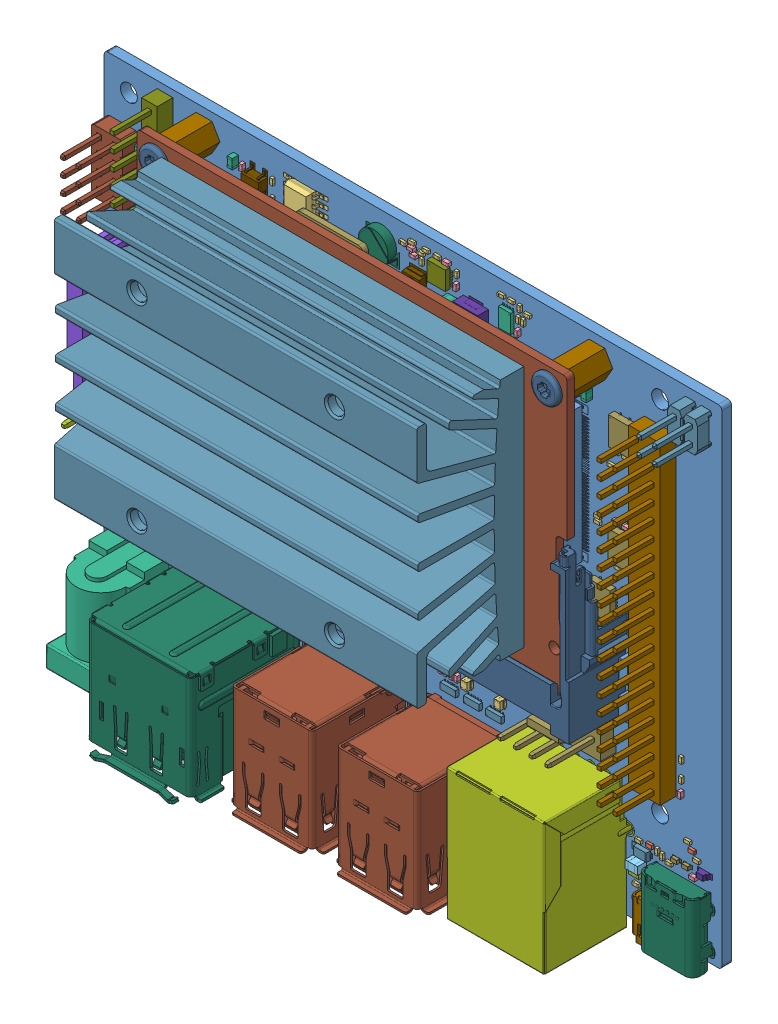
SolidWorks assembly P3450_P3449_A02_P3448_A02, configuration Default. Lengths in mm.
Overall size (100 81.03 30.51).
401 component instances, 71 part files, 0 mates.
Components (placement in the parent):
- 142-13449-1000-A02_ASM-1: 142-13449-1000-A02_ASM [Default] at origin size (100 81.03 23.18)
  - 142-13449-1000-A02-1: 142-13449-1000-A02 [Default] at origin size (100 79 1.57)
  - 315-1109-000_1-1: 315-1109-000_1 [Default] at (5.6 4.9 1.575) x (-1 0 0) z (0 0 1) size (4.5 3.5 0.8)
  - 0402_H040-1: 0402_H040 [Default] at (8 -0.825 1.575) size (1 0.5 0.4)
  - 0402_H060-1: 0402_H060 [Default] at (1 5 1.575) x (0 -1 0) z (0 0 1) size (1 0.5 0.6)
  - 0402_H040-2: 0402_H040 [Default] at (9.9 -0.3 1.575) size (1 0.5 0.4)
  - 0402_H040-3: 0402_H040 [Default] at (8.296 51.194 1.575) x (-1 0 0) z (0 0 1) size (1 0.5 0.4)
  - 0402_H040-4: 0402_H040 [Default] at (76.2 36.9 1.575) x (-1 0 0) z (0 0 1) size (1 0.5 0.4)
  - 0402_H040-5: 0402_H040 [Default] at (37.8 2.87 1.575) x (0 -1 0) z (0 0 1) size (1 0.5 0.4)
  - 0402_H040-6: 0402_H040 [Default] at (38.6 2.87 1.575) x (0 -1 0) z (0 0 1) size (1 0.5 0.4)
  - 0402_H060-2: 0402_H060 [Default] at (14.2 7.7 1.575) x (0 -1 0) z (0 0 1) size (1 0.5 0.6)
  - 0402_H040-7: 0402_H040 [Default] at (64 27.5 1.575) x (-1 0 0) z (0 0 1) size (1 0.5 0.4)
  - 0402_H060-3: 0402_H060 [Default] at (18.6 43.15 1.575) x (-1 0 0) z (0 0 1) size (1 0.5 0.6)
  - 0402_H060-4: 0402_H060 [Default] at (65.5 52.8 1.575) x (0 1 0) z (0 0 1) size (1 0.5 0.6)
  - 0402_H060-5: 0402_H060 [Default] at (64 28.4 1.575) x (-1 0 0) z (0 0 1) size (1 0.5 0.6)
  - 0402_H040-8: 0402_H040 [Default] at (60.95 25.85 1.575) size (1 0.5 0.4)
  - 0402_H060-6: 0402_H060 [Default] at (17.3 7.7 1.575) x (0 -1 0) z (0 0 1) size (1 0.5 0.6)
  - 0402_H060-7: 0402_H060 [Default] at (18.6 7.7 1.575) x (0 -1 0) z (0 0 1) size (1 0.5 0.6)
  - 0402_H060-8: 0402_H060 [Default] at (12.9 7.7 1.575) x (0 -1 0) z (0 0 1) size (1 0.5 0.6)
  - 0402_H060-9: 0402_H060 [Default] at (80.9 37.7 1.575) x (-1 0 0) z (0 0 1) size (1 0.5 0.6)
  - 0402_H040-9: 0402_H040 [Default] at (79.5 31.3 1.575) size (1 0.5 0.4)
  - 0402_H040-10: 0402_H040 [Default] at (81 31.3 1.575) x (-1 0 0) z (0 0 1) size (1 0.5 0.4)
  - 0402_H060-10: 0402_H060 [Default] at (79.3 37.7 1.575) size (1 0.5 0.6)
  - 0402_H060-11: 0402_H060 [Default] at (74.8 4.05 1.575) x (-1 0 0) z (0 0 1) size (1 0.5 0.6)
  - 0402_H040-11: 0402_H040 [Default] at (65.675 6.15 1.575) x (0 -1 0) z (0 0 1) size (1 0.5 0.4)
  - 0402_H060-12: 0402_H060 [Default] at (67.7 6.85 1.575) x (0 1 0) z (0 0 1) size (1 0.5 0.6)
  - 0402_H040-12: 0402_H040 [Default] at (64.475 5.8 1.575) x (-1 0 0) z (0 0 1) size (1 0.5 0.4)
  - 0402_H040-13: 0402_H040 [Default] at (67.725 5.325 1.575) x (0 1 0) z (0 0 1) size (1 0.5 0.4)
  - 0402_H060-13: 0402_H060 [Default] at (46.1 59.45 1.575) size (1 0.5 0.6)
  - 0402_H040-14: 0402_H040 [Default] at (44.65 59.45 1.575) size (1 0.5 0.4)
  - 0402_H040-15: 0402_H040 [Default] at (46.1 60.25 1.575) size (1 0.5 0.4)
  - 0402_H060-14: 0402_H060 [Default] at (53.35 57.7 1.575) x (0 -1 0) z (0 0 1) size (1 0.5 0.6)
  - 0402_H040-16: 0402_H040 [Default] at (47.6 59.45 1.575) size (1 0.5 0.4)
  - 0402_H040-17: 0402_H040 [Default] at (48.4 60.25 1.575) size (1 0.5 0.4)
  - 0402_H040-18: 0402_H040 [Default] at (47.7 58.325 1.575) x (0 1 0) z (0 0 1) size (1 0.5 0.4)
  - 0402_H060-15: 0402_H060 [Default] at (46.5 58.65 1.575) x (-1 0 0) z (0 0 1) size (1 0.5 0.6)
  - 0402_H060-16: 0402_H060 [Default] at (51.8 60.25 1.575) size (1 0.5 0.6)
  - 0402_H040-19: 0402_H040 [Default] at (53.35 59.4 1.575) x (0 -1 0) z (0 0 1) size (1 0.5 0.4)
  - 0402_H040-20: 0402_H040 [Default] at (50.2 60.25 1.575) x (-1 0 0) z (0 0 1) size (1 0.5 0.4)
  - 0402_H060-17: 0402_H060 [Default] at (18.6 43.95 1.575) x (-1 0 0) z (0 0 1) size (1 0.5 0.6)
  - 0402_H060-18: 0402_H060 [Default] at (52.75 2.9 1.575) x (0 -1 0) z (0 0 1) size (1 0.5 0.6)
  - 0402_H060-19: 0402_H060 [Default] at (22.35 47.4 1.575) x (-1 0 0) z (0 0 1) size (1 0.5 0.6)
  - 0402_H060-20: 0402_H060 [Default] at (20.55 47.4 1.575) x (-1 0 0) z (0 0 1) size (1 0.5 0.6)
  - 0402_H060-21: 0402_H060 [Default] at (21.95 34.55 1.575) x (0 -1 0) z (0 0 1) size (1 0.5 0.6)
  - 0402_H060-22: 0402_H060 [Default] at (21.05 34.55 1.575) x (0 -1 0) z (0 0 1) size (1 0.5 0.6)
  - 0402_H060-23: 0402_H060 [Default] at (53.55 2.9 1.575) x (0 -1 0) z (0 0 1) size (1 0.5 0.6)
  - 0402_H060-24: 0402_H060 [Default] at (25.4 54 1.575) x (-1 0 0) z (0 0 1) size (1 0.5 0.6)
  - 0402_H060-25: 0402_H060 [Default] at (24 34.58 1.575) x (0 -1 0) z (0 0 1) size (1 0.5 0.6)
  - 0402_H040-21: 0402_H040 [Default] at (55.6 2.95 1.575) x (0 -1 0) z (0 0 1) size (1 0.5 0.4)
  - 0402_H040-22: 0402_H040 [Default] at (20.13 34.53 1.575) x (0 1 0) z (0 0 1) size (1 0.5 0.4)
  - 0402_H060-26: 0402_H060 [Default] at (18.4 35.15 1.575) x (0 1 0) z (0 0 1) size (1 0.5 0.6)
  - 0402_H060-27: 0402_H060 [Default] at (18.4 36.75 1.575) x (0 1 0) z (0 0 1) size (1 0.5 0.6)
  - 0402_H040-23: 0402_H040 [Default] at (39.6 2.87 1.575) x (0 -1 0) z (0 0 1) size (1 0.5 0.4)
  - 0402_H040-24: 0402_H040 [Default] at (40.4 2.87 1.575) x (0 -1 0) z (0 0 1) size (1 0.5 0.4)
  - 0402_H040-25: 0402_H040 [Default] at (60.95 2.95 1.575) x (0 -1 0) z (0 0 1) size (1 0.5 0.4)
  - 0402_H040-26: 0402_H040 [Default] at (60.15 2.95 1.575) x (0 -1 0) z (0 0 1) size (1 0.5 0.4)
  - 0402_H040-27: 0402_H040 [Default] at (54.8 2.95 1.575) x (0 -1 0) z (0 0 1) size (1 0.5 0.4)
  - 0402_H040-28: 0402_H040 [Default] at (31.6 54 1.575) size (1 0.5 0.4)
  - 0402_H040-29: 0402_H040 [Default] at (27.4 54 1.575) size (1 0.5 0.4)
  - 0402_H040-30: 0402_H040 [Default] at (29.6 54 1.575) x (-1 0 0) z (0 0 1) size (1 0.5 0.4)
  - 0402_H040-31: 0402_H040 [Default] at (63.775 -14.475 1.575) size (1 0.5 0.4)
  - 0402_H040-32: 0402_H040 [Default] at (63.775 -15.275 1.575) size (1 0.5 0.4)
  - 0402_H040-33: 0402_H040 [Default] at (8.025 41.475 1.575) x (-1 0 0) z (0 0 1) size (1 0.5 0.4)
  - 0402_H060-28: 0402_H060 [Default] at (63.95 1.25 1.575) x (0 1 0) z (0 0 1) size (1 0.5 0.6)
  - 0402_H060-29: 0402_H060 [Default] at (2.95 54.05 1.575) x (0 1 0) z (0 0 1) size (1 0.5 0.6)
  - 0402_H040-34: 0402_H040 [Default] at (92.2 -3.45 1.575) x (-1 0 0) z (0 0 1) size (1 0.5 0.4)
  - 0402_H060-30: 0402_H060 [Default] at (32.85 7.7 1.575) x (0 -1 0) z (0 0 1) size (1 0.5 0.6)
  - 0402_H060-31: 0402_H060 [Default] at (27.25 7.7 1.575) x (0 -1 0) z (0 0 1) size (1 0.5 0.6)
  - 0402_H060-32: 0402_H060 [Default] at (31.25 7.7 1.575) x (0 -1 0) z (0 0 1) size (1 0.5 0.6)
  - 0402_H060-33: 0402_H060 [Default] at (28.85 7.7 1.575) x (0 -1 0) z (0 0 1) size (1 0.5 0.6)
  - 0402_H060-34: 0402_H060 [Default] at (32.05 7.7 1.575) x (0 -1 0) z (0 0 1) size (1 0.5 0.6)
  - 0402_H060-35: 0402_H060 [Default] at (28.05 7.7 1.575) x (0 -1 0) z (0 0 1) size (1 0.5 0.6)
  - 0402_H060-36: 0402_H060 [Default] at (30.45 7.7 1.575) x (0 -1 0) z (0 0 1) size (1 0.5 0.6)
  - 0402_H060-37: 0402_H060 [Default] at (29.65 7.7 1.575) x (0 -1 0) z (0 0 1) size (1 0.5 0.6)
  - 0402_H060-38: 0402_H060 [Default] at (24.65 6.41 1.575) x (0 -1 0) z (0 0 1) size (1 0.5 0.6)
  - 0402_H060-39: 0402_H060 [Default] at (25.85 6.41 1.575) x (0 -1 0) z (0 0 1) size (1 0.5 0.6)
  - 0402_H060-40: 0402_H060 [Default] at (4.2 36.5 1.575) x (0 1 0) z (0 0 1) size (1 0.5 0.6)
  - 0402_H060-41: 0402_H060 [Default] at (89.7 4.7 1.575) x (0 -1 0) z (0 0 1) size (1 0.5 0.6)
  - 0402_H060-42: 0402_H060 [Default] at (82.5 3.8 1.575) x (0 -1 0) z (0 0 1) size (1 0.5 0.6)
  - 0402_H060-43: 0402_H060 [Default] at (12.65 49.7 1.575) size (1 0.5 0.6)
  - 0402_H060-44: 0402_H060 [Default] at (11.2 50.15 1.575) x (0 -1 0) z (0 0 1) size (1 0.5 0.6)
  - 0402_H060-45: 0402_H060 [Default] at (26.5 34.55 1.575) x (0 -1 0) z (0 0 1) size (1 0.5 0.6)
  - 0402_H060-46: 0402_H060 [Default] at (29.9 34.5 1.575) x (0 -1 0) z (0 0 1) size (1 0.5 0.6)
  - 0402_H060-47: 0402_H060 [Default] at (31.7 40.15 1.575) x (0 1 0) z (0 0 1) size (1 0.5 0.6)
  - 0402_H060-48: 0402_H060 [Default] at (31.15 42.5 1.575) x (0 1 0) z (0 0 1) size (1 0.5 0.6)
  - 0402_H060-49: 0402_H060 [Default] at (19.2 47.05 1.575) x (0 1 0) z (0 0 1) size (1 0.5 0.6)
  - 0402_H060-50: 0402_H060 [Default] at (17.95 42 1.575) x (0 -1 0) z (0 0 1) size (1 0.5 0.6)
  - 0402_H060-51: 0402_H060 [Default] at (27.3 48.25 1.575) x (0 1 0) z (0 0 1) size (1 0.5 0.6)
  - 0402_H060-52: 0402_H060 [Default] at (31.7 37.85 1.575) x (0 -1 0) z (0 0 1) size (1 0.5 0.6)
  - 0402_H060-53: 0402_H060 [Default] at (29.6 48.35 1.575) x (0 1 0) z (0 0 1) size (1 0.5 0.6)
  - 0402_H060-54: 0402_H060 [Default] at (18.8 38.75 1.575) x (-1 0 0) z (0 0 1) size (1 0.5 0.6)
  - 0402_H060-55: 0402_H060 [Default] at (18.7 57.2 1.575) x (0 -1 0) z (0 0 1) size (1 0.5 0.6)
  - 0402_H060-56: 0402_H060 [Default] at (34.1 2.9 1.575) x (0 -1 0) z (0 0 1) size (1 0.5 0.6)
  - 0402_H060-57: 0402_H060 [Default] at (35.8 2.9 1.575) x (0 -1 0) z (0 0 1) size (1 0.5 0.6)
  - 0402_H060-58: 0402_H060 [Default] at (34.9 2.9 1.575) x (0 -1 0) z (0 0 1) size (1 0.5 0.6)
  - 0402_H060-59: 0402_H060 [Default] at (36.6 2.9 1.575) x (0 -1 0) z (0 0 1) size (1 0.5 0.6)
  - 0402_H060-60: 0402_H060 [Default] at (11.325 44.725 1.575) size (1 0.5 0.6)
  - 0402_H060-61: 0402_H060 [Default] at (50.95 2.9 1.575) x (0 -1 0) z (0 0 1) size (1 0.5 0.6)
  - 0402_H060-62: 0402_H060 [Default] at (51.75 2.9 1.575) x (0 -1 0) z (0 0 1) size (1 0.5 0.6)
  - 0402_H060-63: 0402_H060 [Default] at (11.55 39.7 1.575) size (1 0.5 0.6)
  - 0402_H060-64: 0402_H060 [Default] at (9.5 -8.5 1.575) x (-1 0 0) z (0 0 1) size (1 0.5 0.6)
  - 0402_H060-65: 0402_H060 [Default] at (61.35 38.05 1.575) x (0 -1 0) z (0 0 1) size (1 0.5 0.6)
  - 0402_H060-66: 0402_H060 [Default] at (60.55 38.05 1.575) x (0 -1 0) z (0 0 1) size (1 0.5 0.6)
  - 0402_H060-67: 0402_H060 [Default] at (29.3 25.65 1.575) x (0 -1 0) z (0 0 1) size (1 0.5 0.6)
  - 0402_H060-68: 0402_H060 [Default] at (63.3 56.2 1.575) x (0 1 0) z (0 0 1) size (1 0.5 0.6)
  - 0402_H060-69: 0402_H060 [Default] at (20.5 54.2 1.575) size (1 0.5 0.6)
  - 0402_H060-70: 0402_H060 [Default] at (60.1 32.15 1.575) x (0 1 0) z (0 0 1) size (1 0.5 0.6)
  - 0402_H060-71: 0402_H060 [Default] at (60.9 32.15 1.575) x (0 1 0) z (0 0 1) size (1 0.5 0.6)
  - 0402_H060-72: 0402_H060 [Default] at (18.6 44.85 1.575) size (1 0.5 0.6)
  - 0402_H060-73: 0402_H060 [Default] at (18.6 45.65 1.575) size (1 0.5 0.6)
  - 0402_H060-74: 0402_H060 [Default] at (18.1 27.25 1.575) size (1 0.5 0.6)
  - 0402_H060-75: 0402_H060 [Default] at (15.1 7.7 1.575) x (0 -1 0) z (0 0 1) size (1 0.5 0.6)
  - 0402_H060-76: 0402_H060 [Default] at (16.4 7.7 1.575) x (0 -1 0) z (0 0 1) size (1 0.5 0.6)
  - 0402_H060-77: 0402_H060 [Default] at (20.8 7.7 1.575) x (0 -1 0) z (0 0 1) size (1 0.5 0.6)
  - 0402_H060-78: 0402_H060 [Default] at (19.5 7.7 1.575) x (0 -1 0) z (0 0 1) size (1 0.5 0.6)
  - 0402_H060-79: 0402_H060 [Default] at (21.9 2.8 1.575) size (1 0.5 0.6)
  - 0402_H060-80: 0402_H060 [Default] at (12.75 29 1.575) size (1 0.5 0.6)
  - 0402_H060-81: 0402_H060 [Default] at (10.225 5.1 1.575) size (1 0.5 0.6)
  - 0402_H060-82: 0402_H060 [Default] at (22.8 27.65 1.575) x (0 1 0) z (0 0 1) size (1 0.5 0.6)
  - 0402_H060-83: 0402_H060 [Default] at (18.85 25.15 1.575) x (0 -1 0) z (0 0 1) size (1 0.5 0.6)
  - 0402_H060-84: 0402_H060 [Default] at (17.95 40.1 1.575) x (0 1 0) z (0 0 1) size (1 0.5 0.6)
  - 0402_H040-35: 0402_H040 [Default] at (20.8 6.2 1.575) x (0 1 0) z (0 0 1) size (1 0.5 0.4)
  - 0402_H040-36: 0402_H040 [Default] at (76 22.7 1.575) size (1 0.5 0.4)
  - 0402_H040-37: 0402_H040 [Default] at (23.7 26.85 1.575) x (0 1 0) z (0 0 1) size (1 0.5 0.4)
  - 0402_H040-38: 0402_H040 [Default] at (18 25.15 1.575) x (0 1 0) z (0 0 1) size (1 0.5 0.4)
  - 0402_H040-39: 0402_H040 [Default] at (17.3 28.25 1.575) x (-1 0 0) z (0 0 1) size (1 0.5 0.4)
  - 0402_H040-40: 0402_H040 [Default] at (13.15 4.2 1.575) x (0 -1 0) z (0 0 1) size (1 0.5 0.4)
  - 0402_H040-41: 0402_H040 [Default] at (17.2 30.15 1.575) x (0 -1 0) z (0 0 1) size (1 0.5 0.4)
  - 0402_H040-42: 0402_H040 [Default] at (14.2 6.2 1.575) x (0 1 0) z (0 0 1) size (1 0.5 0.4)
  - 0402_H040-43: 0402_H040 [Default] at (12.9 6.2 1.575) x (0 1 0) z (0 0 1) size (1 0.5 0.4)
  - 0402_H040-44: 0402_H040 [Default] at (15.1 6.2 1.575) x (0 1 0) z (0 0 1) size (1 0.5 0.4)
  - 0402_H040-45: 0402_H040 [Default] at (16.4 6.2 1.575) x (0 1 0) z (0 0 1) size (1 0.5 0.4)
  - 0402_H040-46: 0402_H040 [Default] at (19.5 6.2 1.575) x (0 1 0) z (0 0 1) size (1 0.5 0.4)
  - 0402_H040-47: 0402_H040 [Default] at (17.3 6.2 1.575) x (0 1 0) z (0 0 1) size (1 0.5 0.4)
  - 0402_H040-48: 0402_H040 [Default] at (18.6 6.2 1.575) x (0 1 0) z (0 0 1) size (1 0.5 0.4)
  - 0402_H040-49: 0402_H040 [Default] at (24.2 24.55 1.575) x (0 1 0) z (0 0 1) size (1 0.5 0.4)
  - 0402_H040-50: 0402_H040 [Default] at (23.5 54.9 1.575) x (0 1 0) z (0 0 1) size (1 0.5 0.4)
  - 0402_H040-51: 0402_H040 [Default] at (13.2 39.75 1.575) x (-1 0 0) z (0 0 1) size (1 0.5 0.4)
  - 0402_H040-52: 0402_H040 [Default] at (80.7 47.4 1.575) x (-1 0 0) z (0 0 1) size (1 0.5 0.4)
  - 0402_H040-53: 0402_H040 [Default] at (77.5 22.7 1.575) x (-1 0 0) z (0 0 1) size (1 0.5 0.4)
  - 0402_H040-54: 0402_H040 [Default] at (9.25 -12.75 1.575) x (-1 0 0) z (0 0 1) size (1 0.5 0.4)
  - 0402_H040-55: 0402_H040 [Default] at (9.25 -11.95 1.575) x (-1 0 0) z (0 0 1) size (1 0.5 0.4)
  - 0402_H040-56: 0402_H040 [Default] at (64.475 6.7 1.575) size (1 0.5 0.4)
  - 0402_H040-57: 0402_H040 [Default] at (29.3 24 1.575) x (0 1 0) z (0 0 1) size (1 0.5 0.4)
  - 0402_H040-58: 0402_H040 [Default] at (64.2 32.5 1.575) x (0 1 0) z (0 0 1) size (1 0.5 0.4)
  - 0402_H040-59: 0402_H040 [Default] at (64.15 47.45 1.575) x (0 -1 0) z (0 0 1) size (1 0.5 0.4)
  - 0402_H040-60: 0402_H040 [Default] at (64.2 31 1.575) x (0 -1 0) z (0 0 1) size (1 0.5 0.4)
  - 0402_H040-61: 0402_H040 [Default] at (76.2 36.1 1.575) x (-1 0 0) z (0 0 1) size (1 0.5 0.4)
  - 0402_H040-62: 0402_H040 [Default] at (78.4 45.15 1.575) size (1 0.5 0.4)
  - 0402_H040-63: 0402_H040 [Default] at (81.7 38.6 1.575) size (1 0.5 0.4)
  - 0402_H040-64: 0402_H040 [Default] at (81.7 39.4 1.575) size (1 0.5 0.4)
  - 0402_H040-65: 0402_H040 [Default] at (59.35 51.825 1.575) size (1 0.5 0.4)
  - 0402_H040-66: 0402_H040 [Default] at (60.825 51.825 1.575) x (-1 0 0) z (0 0 1) size (1 0.5 0.4)
  - 0402_H040-67: 0402_H040 [Default] at (89.7 9.5 1.575) x (0 1 0) z (0 0 1) size (1 0.5 0.4)
  - 0402_H040-68: 0402_H040 [Default] at (89.7 6.7 1.575) x (0 1 0) z (0 0 1) size (1 0.5 0.4)
  - 0402_H040-69: 0402_H040 [Default] at (3.9 34.2 1.575) x (0 -1 0) z (0 0 1) size (1 0.5 0.4)
  - 0402_H040-70: 0402_H040 [Default] at (5.1 35 1.575) x (0 1 0) z (0 0 1) size (1 0.5 0.4)
  - 0402_H040-71: 0402_H040 [Default] at (32.85 5.81 1.575) x (0 -1 0) z (0 0 1) size (1 0.5 0.4)
  - 0402_H040-72: 0402_H040 [Default] at (32.05 5.81 1.575) x (0 -1 0) z (0 0 1) size (1 0.5 0.4)
  - 0402_H040-73: 0402_H040 [Default] at (27.25 5.81 1.575) x (0 -1 0) z (0 0 1) size (1 0.5 0.4)
  - 0402_H040-74: 0402_H040 [Default] at (28.05 5.81 1.575) x (0 -1 0) z (0 0 1) size (1 0.5 0.4)
  - 0402_H040-75: 0402_H040 [Default] at (31.25 5.81 1.575) x (0 -1 0) z (0 0 1) size (1 0.5 0.4)
  - 0402_H040-76: 0402_H040 [Default] at (30.45 5.81 1.575) x (0 -1 0) z (0 0 1) size (1 0.5 0.4)
  - 0402_H040-77: 0402_H040 [Default] at (28.85 5.81 1.575) x (0 -1 0) z (0 0 1) size (1 0.5 0.4)
  - 0402_H040-78: 0402_H040 [Default] at (29.65 5.81 1.575) x (0 -1 0) z (0 0 1) size (1 0.5 0.4)
  - 0402_H040-79: 0402_H040 [Default] at (13.5 52.9 1.575) x (-1 0 0) z (0 0 1) size (1 0.5 0.4)
  - 0402_H040-80: 0402_H040 [Default] at (22.35 4 1.575) x (0 -1 0) z (0 0 1) size (1 0.5 0.4)
  - 0402_H040-81: 0402_H040 [Default] at (21.55 4 1.575) x (0 1 0) z (0 0 1) size (1 0.5 0.4)
  - 0402_H040-82: 0402_H040 [Default] at (25.85 4.9 1.575) x (0 -1 0) z (0 0 1) size (1 0.5 0.4)
  - 0402_H040-83: 0402_H040 [Default] at (11.8 52.9 1.575) size (1 0.5 0.4)
  - 0402_H040-84: 0402_H040 [Default] at (9.432 51.594 1.575) x (0 -1 0) z (0 0 1) size (1 0.5 0.4)
  - 0402_H040-85: 0402_H040 [Default] at (8.975 50.3 1.575) size (1 0.5 0.4)
  - 0402_H040-86: 0402_H040 [Default] at (82.8 -5.3 1.575) x (-1 0 0) z (0 0 1) size (1 0.5 0.4)
  - 0402_H040-87: 0402_H040 [Default] at (82.4 -11.6 1.575) x (-1 0 0) z (0 0 1) size (1 0.5 0.4)
  - 0402_H040-88: 0402_H040 [Default] at (22.8 26.05 1.575) x (0 1 0) z (0 0 1) size (1 0.5 0.4)
  - 0402_H040-89: 0402_H040 [Default] at (20.8 28.25 1.575) size (1 0.5 0.4)
  - 0402_H040-90: 0402_H040 [Default] at (20.8 24.65 1.575) x (-1 0 0) z (0 0 1) size (1 0.5 0.4)
  - 0402_H040-91: 0402_H040 [Default] at (18.1 26.45 1.575) size (1 0.5 0.4)
  - 0402_H040-92: 0402_H040 [Default] at (24.65 8.41 1.575) x (0 1 0) z (0 0 1) size (1 0.5 0.4)
  - 0402_H040-93: 0402_H040 [Default] at (25.85 8.41 1.575) x (0 1 0) z (0 0 1) size (1 0.5 0.4)
  - 0402_H040-94: 0402_H040 [Default] at (3.8 54.4 1.575) x (0 -1 0) z (0 0 1) size (1 0.5 0.4)
  - 0402_H040-95: 0402_H040 [Default] at (2.45 44.45 1.575) x (0 -1 0) z (0 0 1) size (1 0.5 0.4)
  - 0402_H040-96: 0402_H040 [Default] at (24.65 4.9 1.575) x (0 1 0) z (0 0 1) size (1 0.5 0.4)
  - 0402_H040-97: 0402_H040 [Default] at (22.15 7.6 1.575) x (-1 0 0) z (0 0 1) size (1 0.5 0.4)
  - 0402_H040-98: 0402_H040 [Default] at (79.2 47.4 1.575) size (1 0.5 0.4)
  - 0402_H040-99: 0402_H040 [Default] at (19 28.25 1.575) size (1 0.5 0.4)
  - 0402_H040-100: 0402_H040 [Default] at (9.65 9.7 1.575) x (0 -1 0) z (0 0 1) size (1 0.5 0.4)
  - 0402_H040-101: 0402_H040 [Default] at (28.35 34.45 1.575) x (0 1 0) z (0 0 1) size (1 0.5 0.4)
  - 0402_H040-102: 0402_H040 [Default] at (25.2 34.55 1.575) x (0 1 0) z (0 0 1) size (1 0.5 0.4)
  - 0402_H040-103: 0402_H040 [Default] at (10.625 6.35 1.575) x (0 -1 0) z (0 0 1) size (1 0.5 0.4)
  - 0402_H040-104: 0402_H040 [Default] at (9.825 6.35 1.575) x (0 1 0) z (0 0 1) size (1 0.5 0.4)
  - 0402_H040-105: 0402_H040 [Default] at (4.775 42.975 1.575) x (0 1 0) z (0 0 1) size (1 0.5 0.4)
  - 0402_H040-106: 0402_H040 [Default] at (19.8 32.9 1.575) x (-1 0 0) z (0 0 1) size (1 0.5 0.4)
  - 0402_H040-107: 0402_H040 [Default] at (22.35 24.65 1.575) x (-1 0 0) z (0 0 1) size (1 0.5 0.4)
  - 0402_H040-108: 0402_H040 [Default] at (62.4 54.7 1.575) size (1 0.5 0.4)
  - 0402_H040-109: 0402_H040 [Default] at (62.2 60.05 1.575) x (-1 0 0) z (0 0 1) size (1 0.5 0.4)
  - 0402_H040-110: 0402_H040 [Default] at (23.5 57.5 1.575) x (0 1 0) z (0 0 1) size (1 0.5 0.4)
  - 0402_H040-111: 0402_H040 [Default] at (12.8 44.725 1.575) size (1 0.5 0.4)
  - 0402_H040-112: 0402_H040 [Default] at (21.8 31.45 1.575) x (0 1 0) z (0 0 1) size (1 0.5 0.4)
  - 0402_H040-113: 0402_H040 [Default] at (19.25 34.55 1.575) x (0 1 0) z (0 0 1) size (1 0.5 0.4)
  - 0402_H040-114: 0402_H040 [Default] at (0.95 41.55 1.575) size (1 0.5 0.4)
  - 0402_H040-115: 0402_H040 [Default] at (64.1 58 1.575) x (0 1 0) z (0 0 1) size (1 0.5 0.4)
  - 0402_H040-116: 0402_H040 [Default] at (63.3 58 1.575) x (0 -1 0) z (0 0 1) size (1 0.5 0.4)
  - 0402_H040-117: 0402_H040 [Default] at (63.55 59.7 1.575) x (0 -1 0) z (0 0 1) size (1 0.5 0.4)
  - 0402_H060-85: 0402_H060 [Default] at (71.175 4 1.575) x (-1 0 0) z (0 0 1) size (1 0.5 0.6)
  - 0402_H040-118: 0402_H040 [Default] at (86.6 -5.6 1.575) x (0 1 0) z (0 0 1) size (1 0.5 0.4)
  - 0402_H040-119: 0402_H040 [Default] at (85.8 -5.3 1.575) x (0 1 0) z (0 0 1) size (1 0.5 0.4)
  - 0402_H040-120: 0402_H040 [Default] at (10.25 51.6 1.575) x (0 1 0) z (0 0 1) size (1 0.5 0.4)
  - 0402_H040-121: 0402_H040 [Default] at (80.5 28.55 1.575) size (1 0.5 0.4)
  - 0402_H040-122: 0402_H040 [Default] at (13.95 4.2 1.575) x (0 -1 0) z (0 0 1) size (1 0.5 0.4)
  - 0402_H040-123: 0402_H040 [Default] at (15.35 4.2 1.575) x (0 -1 0) z (0 0 1) size (1 0.5 0.4)
  - 0402_H040-124: 0402_H040 [Default] at (16.15 4.2 1.575) x (0 -1 0) z (0 0 1) size (1 0.5 0.4)
  - 0402_H040-125: 0402_H040 [Default] at (20.55 4.2 1.575) x (0 -1 0) z (0 0 1) size (1 0.5 0.4)
  - 0402_H040-126: 0402_H040 [Default] at (19.75 4.2 1.575) x (0 -1 0) z (0 0 1) size (1 0.5 0.4)
  - 0402_H040-127: 0402_H040 [Default] at (17.6 4.2 1.575) x (0 -1 0) z (0 0 1) size (1 0.5 0.4)
  - 0402_H040-128: 0402_H040 [Default] at (18.4 4.2 1.575) x (0 -1 0) z (0 0 1) size (1 0.5 0.4)
  - 0402_H060-86: 0402_H060 [Default] at (64.25 -13.325 1.575) x (0 -1 0) z (0 0 1) size (1 0.5 0.6)
  - 0402_H060-87: 0402_H060 [Default] at (64.225 -11.825 1.575) x (0 1 0) z (0 0 1) size (1 0.5 0.6)
  - 0402_H040-129: 0402_H040 [Default] at (63.8 -6.85 1.575) x (0 1 0) z (0 0 1) size (1 0.5 0.4)
  - 0402_H040-130: 0402_H040 [Default] at (81.7 41.95 1.575) size (1 0.5 0.4)
  - 0402_H040-131: 0402_H040 [Default] at (87.75 -6 1.575) x (-1 0 0) z (0 0 1) size (1 0.5 0.4)
  - 0402_H040-132: 0402_H040 [Default] at (82.4 -13.6 1.575) x (-1 0 0) z (0 0 1) size (1 0.5 0.4)
  - 0402_H060-88: 0402_H060 [Default] at (91.75 -5.95 1.575) size (1 0.5 0.6)
  - 0402_H040-133: 0402_H040 [Default] at (3.65 49.25 1.575) x (0 -1 0) z (0 0 1) size (1 0.5 0.4)
  - 0402_H040-134: 0402_H040 [Default] at (2.45 49.25 1.575) x (0 1 0) z (0 0 1) size (1 0.5 0.4)
  - 0402_H040-135: 0402_H040 [Default] at (90.75 -1.45 1.575) x (-1 0 0) z (0 0 1) size (1 0.5 0.4)
  - 0402_H040-136: 0402_H040 [Default] at (8.45 39.55 1.575) x (0 -1 0) z (0 0 1) size (1 0.5 0.4)
  - 0402_H060-89: 0402_H060 [Default] at (8.85 -5.25 1.575) x (-1 0 0) z (0 0 1) size (1 0.5 0.6)
  - 0402_H040-137: 0402_H040 [Default] at (18.6 32.55 1.575) x (0 1 0) z (0 0 1) size (1 0.5 0.4)
  - 0402_H060-90: 0402_H060 [Default] at (4.5 44.45 1.575) x (0 1 0) z (0 0 1) size (1 0.5 0.6)
  - 0402_H040-138: 0402_H040 [Default] at (8.35 2.75 1.575) size (1 0.5 0.4)
  - 0402_H040-139: 0402_H040 [Default] at (9.4 1.95 1.575) size (1 0.5 0.4)
  - 0402_H040-140: 0402_H040 [Default] at (8.2 1.55 1.575) x (0 1 0) z (0 0 1) size (1 0.5 0.4)
  - 0402_H060-91: 0402_H060 [Default] at (8.5 3.875 1.575) x (0 -1 0) z (0 0 1) size (1 0.5 0.6)
  - 0402_H060-92: 0402_H060 [Default] at (-0.8 41.5 1.575) x (-1 0 0) z (0 0 1) size (1 0.5 0.6)
  - 0402_H040-141: 0402_H040 [Default] at (-1.35 7.75 1.575) size (1 0.5 0.4)
  - 0402_H040-142: 0402_H040 [Default] at (8 0.425 1.575) size (1 0.5 0.4)
  - 0402_H040-143: 0402_H040 [Default] at (67.9 4.025 1.575) x (-1 0 0) z (0 0 1) size (1 0.5 0.4)
  - 0402_H040-144: 0402_H040 [Default] at (60.6 60.05 1.575) x (-1 0 0) z (0 0 1) size (1 0.5 0.4)
  - 0402_H040-145: 0402_H040 [Default] at (72.85 4 1.575) x (-1 0 0) z (0 0 1) size (1 0.5 0.4)
  - 0402_H040-146: 0402_H040 [Default] at (64.8 59.35 1.575) size (1 0.5 0.4)
  - 0402_H040-147: 0402_H040 [Default] at (7.2 7.3 1.575) size (1 0.5 0.4)
  - 0402_H040-148: 0402_H040 [Default] at (8.5 5.35 1.575) x (0 1 0) z (0 0 1) size (1 0.5 0.4)
  - 0402_H040-149: 0402_H040 [Default] at (8.475 7.075 1.575) x (0 1 0) z (0 0 1) size (1 0.5 0.4)
  - VIRTUAL_SHORT-1: VIRTUAL_SHORT [Default] at (23.5 32.9 1.575) x (0 1 0) z (0 0 1) size (0.25 0.25 1)
  - VIRTUAL_SHORT-2: VIRTUAL_SHORT [Default] at (26.85 32.85 1.575) x (0 1 0) z (0 0 1) size (0.25 0.25 1)
  - VIRTUAL_SHORT-3: VIRTUAL_SHORT [Default] at (30.6 33.8 1.575) x (0 1 0) z (0 0 1) size (0.25 0.25 1)
  - VIRTUAL_SHORT-4: VIRTUAL_SHORT [Default] at (32.65 39.75 1.575) x (-1 0 0) z (0 0 1) size (0.25 0.25 1)
  - VIRTUAL_SHORT-5: VIRTUAL_SHORT [Default] at (31.85 42.1 1.575) x (-1 0 0) z (0 0 1) size (0.25 0.25 1)
  - VIRTUAL_SHORT-6: VIRTUAL_SHORT [Default] at (17.35 42.4 1.575) size (0.25 0.25 1)
  - VIRTUAL_SHORT-7: VIRTUAL_SHORT [Default] at (18.6 46.6 1.575) size (0.25 0.25 1)
  - VIRTUAL_SHORT-8: VIRTUAL_SHORT [Default] at (20.9 32.9 1.575) x (0 1 0) z (0 0 1) size (0.25 0.25 1)
  - VIRTUAL_SHORT-9: VIRTUAL_SHORT [Default] at (28.6 48.25 1.575) x (0 -1 0) z (0 0 1) size (0.25 0.25 1)
  - VIRTUAL_SHORT-10: VIRTUAL_SHORT [Default] at (27.1 49.35 1.575) x (0 -1 0) z (0 0 1) size (0.25 0.25 1)
  - VIRTUAL_SHORT-11: VIRTUAL_SHORT [Default] at (22.1 32.95 1.575) x (-1 0 0) z (0 0 1) size (0.25 0.25 1)
  - VIRTUAL_SHORT-12: VIRTUAL_SHORT [Default] at (32.65 38.25 1.575) x (-1 0 0) z (0 0 1) size (0.25 0.25 1)
  - VIRTUAL_SHORT-13: VIRTUAL_SHORT [Default] at (30.3 48 1.575) x (-1 0 0) z (0 0 1) size (0.25 0.25 1)
  - VIRTUAL_SHORT-14: VIRTUAL_SHORT [Default] at (17.15 38.95 1.575) size (0.25 0.25 1)
  - VIRTUAL_SHORT-15: VIRTUAL_SHORT [Default] at (17.15 39.7 1.575) size (0.25 0.25 1)
  - VIRTUAL_SHORT-16: VIRTUAL_SHORT [Default] at (76.175 4.1 1.575) x (-1 0 0) z (0 0 1) size (0.25 0.25 1)
  - 064-0377-000_2-1: 064-0377-000_2 [Default] at (2 -4.75 1.575) x (0 -1 0) z (0 0 1) size (14.63 10.08 14.5)
  - 074-0117-000_2-1: 074-0117-000_2 [Default] at (0.254 14.3 1.575) size (5.08 2.54 11.66)
  - 090-0096-000_1-1: 090-0096-000_1 [Default] at (3.45 44.4 1.575) x (0 -1 0) z (0 0 1) size (1.2 0.6 0.4)
  - 090-0309-000_1-1: 090-0309-000_1 [Default] at (-1.65 8.7 1.575) x (-1 0 0) z (0 0 1) size (1.2 0.6 0.4)
  - 115-1232-000_2-1: 115-1232-000_2 [Default] at (1.25 6.5 1.575) x (-1 0 0) z (0 0 1) size (0.9 0.9 0.33)
  - 074-0102-000_4-1: 074-0102-000_4 [Default] at (0.254 44.36 1.575) x (0 1 0) z (0 0 1) size (10.16 5.08 11.6)
  - 064-0400-000_1-1: 064-0400-000_1 [Default] at (73.75 7.77 1.575) size (10.16 5.8 13.5)
  - MEC_STANDOFF_PTH_620C380P-1: MEC_STANDOFF_PTH_620C380P [Default] at (40.276 40.3 1.575) x (0 1 0) z (0 0 1) size (6.2 6.2 0.73)
  - 090-0231-000_1-1: 090-0231-000_1 [Default] at (35.3 0.7 1.575) x (-1 0 0) z (0 0 1) size (2.5 1.55 0.55)
  - 090-0231-000_1-2: 090-0231-000_1 [Default] at (52.25 0.7 1.575) x (-1 0 0) z (0 0 1) size (2.5 1.55 0.55)
  - 090-0231-000_1-3: 090-0231-000_1 [Default] at (56.05 0.7 1.575) size (2.5 1.55 0.55)
  - 090-0231-000_1-4: 090-0231-000_1 [Default] at (59.65 0.7 1.575) size (2.5 1.55 0.55)
  - 090-0231-000_1-5: 090-0231-000_1 [Default] at (39.1 0.7 1.575) size (2.5 1.55 0.55)
  - 090-0231-000_1-6: 090-0231-000_1 [Default] at (43.1 0.7 1.575) size (2.5 1.55 0.55)
  - 090-0231-000_1-7: 090-0231-000_1 [Default] at (14.6 1.8 1.575) size (2.5 1.55 0.55)
  - 090-0231-000_1-8: 090-0231-000_1 [Default] at (19.1 1.8 1.575) size (2.5 1.55 0.55)
  - 090-0231-000_1-9: 090-0231-000_1 [Default] at (22.5 1.4 1.575) size (2.5 1.55 0.55)
  - 090-0231-000_1-10: 090-0231-000_1 [Default] at (28.45 3.35 1.575) size (2.5 1.55 0.55)
  - 090-0231-000_1-11: 090-0231-000_1 [Default] at (31.65 3.35 1.575) size (2.5 1.55 0.55)
  - 064-0305-000_2-1: 064-0305-000_2 [Default] at (90 -12.2 1.575) size (9.87 10.86 4.08)
  - 074-0223-000_2-1: 074-0223-000_2 [Default] at (5.85 53.25 1.575) x (0 1 0) z (0 0 1) size (15.24 2.54 11.6)
  - 131-0832-000_2-1: 131-0832-000_2 [Default] at (56.3 54.7 1.575) x (0 -1 0) z (0 0 1) size (4.96 4.06 1.8)
  - 115-0836-000_1-1: 115-0836-000_1 [Default] at (21.1 56.6 1.575) size (2.9 3.58 1.45)
  - 115-0836-000_1-2: 115-0836-000_1 [Default] at (11.8 42.3 1.575) size (2.9 3.58 1.45)
  - 315-0620-000_1-1: 315-0620-000_1 [Default] at (72.1 53.4 1.575) x (0 -1 0) z (0 0 1) size (2.9 3.58 1.1)
  - 315-1062-000_1-1: 315-1062-000_1 [Default] at (26.8 25.15 1.575) x (0 -1 0) z (0 0 1) size (2.9 3.58 1.45)
  - 170-0285-000_1-1: 170-0285-000_1 [Default] at (28.72 57.28 1.575) x (0 1 0) z (0 0 1) size (4.9 7.21 1.75)
  - 115-0138-000_1-1: 115-0138-000_1 [Default] at (9.15 48.55 1.575) x (0 1 0) z (0 0 1) size (2 2.88 1.1)
  - 115-1821-000_1-1: 115-1821-000_1 [Default] at (3.3 40.8 1.575) x (-1 0 0) z (0 0 1) size (2 2.88 1.1)
  - 115-1821-000_1-2: 115-1821-000_1 [Default] at (6.25 39.55 1.575) x (0 -1 0) z (0 0 1) size (2 2.88 1.1)
  - 115-0742-000_2-1: 115-0742-000_2 [Default] at (3.05 46.85 1.575) size (2 2.88 1.1)
  - 115-0742-000_2-2: 115-0742-000_2 [Default] at (3.05 51.65 1.575) x (-1 0 0) z (0 0 1) size (2 2.88 1.1)
  - 115-1821-000_1-3: 115-1821-000_1 [Default] at (59.6 27.6 1.575) x (0 1 0) z (0 0 1) size (2 2.88 1.1)
  - 091-0022-000_1-1: 091-0022-000_1 [Default] at (-0.95 5.7 1.575) size (2 2.51 1.1)
  - 091-0023-000_1-1: 091-0023-000_1 [Default] at (15.25 29.9 1.575) x (0 -1 0) z (0 0 1) size (2 2.51 1.1)
  - 080-1368-000_1-1: 080-1368-000_1 [Default] at (88 -14.3 1.575) size (8.9 7.51 4.47)
  - 080-1656-000_3-1: 080-1656-000_3 [Default] at (44 16.6 1.575) x (-1 0 0) z (0 0 1) size (77.5 25.85 9.66)
  - 090-0243-000_1-1: 090-0243-000_1 [Default] at (8.5 -4.1 1.575) x (-1 0 0) z (0 0 1) size (1.41 0.61 0.45)
  - 090-0243-000_1-2: 090-0243-000_1 [Default] at (9.95 -3.7 1.575) x (0 1 0) z (0 0 1) size (1.41 0.61 0.45)
  - 090-0243-000_1-3: 090-0243-000_1 [Default] at (9.5 -10.95 1.575) x (-1 0 0) z (0 0 1) size (1.41 0.61 0.45)
  - 090-0243-000_1-4: 090-0243-000_1 [Default] at (9.8 -6.25 1.575) x (-1 0 0) z (0 0 1) size (1.41 0.61 0.45)
  - 090-0243-000_1-5: 090-0243-000_1 [Default] at (9.5 -9.5 1.575) x (-1 0 0) z (0 0 1) size (1.41 0.61 0.45)
  - 090-0172-000_1-1: 090-0172-000_1 [Default] at (90.6 -5 1.575) size (1.41 0.61 0.55)
  - 090-0172-000_1-2: 090-0172-000_1 [Default] at (88.8 -5 1.575) x (-1 0 0) z (0 0 1) size (1.41 0.61 0.55)
  - 115-2177-000_2-1: 115-2177-000_2 [Default] at (12.7 51.35 1.575) x (0 1 0) z (0 0 1) size (1.8 1.71 0.4)
  - 090-0233-000_1-1: 090-0233-000_1 [Default] at (83.5 -6.6 1.575) size (3.3 1.3 0.74)
  - 064-0374-000_2-1: 064-0374-000_2 [Default] at (19.75 -9.65 1.575) size (18.1 18.55 21.85)
  - 115-2628-000_3-1: 115-2628-000_3 [Default] at (25.2 41.2 1.575) size (9.5 9.5 0.9)
  - 092-0073-000_1-1: 092-0073-000_1 [Default] at (93.35 -4.75 1.575) x (-1 0 0) z (0 0 1) size (2.46 0.81 0.9)
  - IND_SMD_0402_H060-1: IND_SMD_0402_H060 [Default] at (12.85 29.9 1.575) x (-1 0 0) z (0 0 1) size (1 0.5 0.6)
  - 1206_H190-1: 1206_H190 [Default] at (82 18.8 1.575) x (0 1 0) z (0 0 1) size (3.22 1.64 1.94)
  - 1206_H190-2: 1206_H190 [Default] at (81.95 13.5 1.575) x (0 -1 0) z (0 0 1) size (3.22 1.64 1.94)
  - 300-0868-000_3-1: 300-0868-000_3 [Default] at (69.6 4 1.575) x (-1 0 0) z (0 0 1) size (1 0.6 0.4)
  - 300-0868-000_3-2: 300-0868-000_3 [Default] at (9.55 0.95 1.575) size (1 0.6 0.4)
  - 300-0868-000_3-3: 300-0868-000_3 [Default] at (19.6 31.45 1.575) x (0 -1 0) z (0 0 1) size (1 0.6 0.4)
  - 300-0868-000_3-4: 300-0868-000_3 [Default] at (91.45 -2.45 1.575) x (-1 0 0) z (0 0 1) size (1 0.6 0.4)
  - 300-0868-000_3-5: 300-0868-000_3 [Default] at (84.6 -5.1 1.575) size (1 0.6 0.4)
  - 300-0868-000_3-6: 300-0868-000_3 [Default] at (66.725 5.875 1.575) x (0 -1 0) z (0 0 1) size (1 0.6 0.4)
  - 300-0868-000_3-7: 300-0868-000_3 [Default] at (20.8 31.45 1.575) x (0 -1 0) z (0 0 1) size (1 0.6 0.4)
  - 300-0868-000_3-8: 300-0868-000_3 [Default] at (62.9 31.35 1.575) x (-1 0 0) z (0 0 1) size (1 0.6 0.4)
  - 300-0868-000_3-9: 300-0868-000_3 [Default] at (65.475 4.8 1.575) x (-1 0 0) z (0 0 1) size (1 0.6 0.4)
  - 300-0868-000_3-10: 300-0868-000_3 [Default] at (63.9 33.85 1.575) x (-1 0 0) z (0 0 1) size (1 0.6 0.4)
  - 300-0868-000_3-11: 300-0868-000_3 [Default] at (15.65 27.9 1.575) size (1 0.6 0.4)
  - 300-0868-000_3-12: 300-0868-000_3 [Default] at (11.8 6.1 1.575) x (0 1 0) z (0 0 1) size (1 0.6 0.4)
  - 300-0868-000_3-13: 300-0868-000_3 [Default] at (22.1 6.25 1.575) x (0 1 0) z (0 0 1) size (1 0.6 0.4)
  - 300-0869-000_3-1: 300-0869-000_3 [Default] at (9.65 8.1 1.575) x (0 -1 0) z (0 0 1) size (1 0.6 0.53)
  - 300-0402-000_1-1: 300-0402-000_1 [Default] at (20.8 26.45 1.575) x (0 -1 0) z (0 0 1) size (2 2.69 1.1)
  - 300-0560-000_1-1: 300-0560-000_1 [Default] at (6.8 43.65 1.575) x (-1 0 0) z (0 0 1) size (2 2.69 1.1)
  - 174-0159-000_2-1: 174-0159-000_2 [Default] at (61.49 57.15 1.575) x (-1 0 0) z (0 0 1) size (2 3.52 0.6)
  - 064-0373-000_2-1: 064-0373-000_2 [Default] at (72.95 -7.825 1.575) size (17.8 21.61 17.45)
  - 064-0375-000_2-1: 064-0375-000_2 [Default] at (19.751 -12.275 1.575) size (16.2 13.69 9.44)
  - 074-0221-000_3-1: 074-0221-000_3 [Default] at (86 29 1.575) x (0 1 0) z (0 0 1) size (50.8 5.08 11.6)
  - 2016MM_H100-1: 2016MM_H100 [Default] at (24.5 49.25 1.575) x (0 1 0) z (0 0 1) size (2.02 1.6 1.02)
  - 065-0656-000_2-1: 065-0656-000_2 [Default] at (55.6 -10.04 1.575) x (-1 0 0) z (0 0 1) size (16.2 17.45 19.62)
  - 065-0656-000_2-2: 065-0656-000_2 [Default] at (38.6 -10.04 1.575) x (-1 0 0) z (0 0 1) size (16.2 17.45 19.62)
  - 115-1921-000_3-1: 115-1921-000_3 [Default] at (80.45 50.52 1.575) x (0 -1 0) z (0 0 1) size (5 4 1)
  - 115-1921-000_3-2: 115-1921-000_3 [Default] at (80.4 34.5 1.575) x (0 -1 0) z (0 0 1) size (5 4 1)
  - 115-1921-000_3-3: 115-1921-000_3 [Default] at (77.2 25.9 1.575) x (0 -1 0) z (0 0 1) size (5 4 1)
  - 085-0328-000_2-1: 085-0328-000_2 [Default] at (16.28 36.32 1.575) x (0 -1 0) z (0 0 1) size (3.81 2.5 0.6)
  - 074-0216-000_2-1: 074-0216-000_2 [Default] at (92.14 58 1.575) x (-1 0 0) z (0 0 1) size (4.83 5 11.5)
  - 060-0002-000_1-1: 060-0002-000_1 [Default] at (41.2 57.9 1.575) x (0 -1 0) z (0 0 1) size (5.1 5.4 1.68)
  - 316-0697-000_1-1: 316-0697-000_1 [Default] at (50.6 58.1 1.575) x (0 -1 0) z (0 0 1) size (3 3.72 0.8)
  - 032-0256-000_1-1: 032-0256-000_1 [Default] at (5.925 9.425 1.575) size (4.22 2.82 2)
  - 041-0092-000_1-1: 041-0092-000_1 [Default] at (46.9 54.9 1.575) x (0 -1 0) z (0 0 1) size (4.22 2.82 1.2)
  - 080-1243-000_3-1: 080-1243-000_3 [Default] at (69.9 40.3 1.575) x (0 -1 0) z (0 0 1) size (21.9 9.1 4.8)
  - 102-0066-000_2-1: 102-0066-000_2 [Default] at (18 4.2 1.575) size (1 1.86 0.61)
  - 102-0066-000_2-2: 102-0066-000_2 [Default] at (13.55 4.2 1.575) size (1 1.86 0.61)
  - 102-0066-000_2-3: 102-0066-000_2 [Default] at (32.45 5.81 1.575) size (1 1.86 0.61)
  - 102-0066-000_2-4: 102-0066-000_2 [Default] at (27.65 5.81 1.575) size (1 1.86 0.61)
  - 102-0066-000_2-5: 102-0066-000_2 [Default] at (20.15 4.2 1.575) size (1 1.86 0.61)
  - 102-0066-000_2-6: 102-0066-000_2 [Default] at (15.75 4.2 1.575) size (1 1.86 0.61)
  - 102-0066-000_2-7: 102-0066-000_2 [Default] at (29.25 5.81 1.575) size (1 1.86 0.61)
  - 102-0066-000_2-8: 102-0066-000_2 [Default] at (30.85 5.81 1.575) size (1 1.86 0.61)
  - 102-0037-000_1-1: 102-0037-000_1 [Default] at (55.2 2.95 1.575) x (-1 0 0) z (0 0 1) size (1 1.86 0.91)
  - 102-0037-000_1-2: 102-0037-000_1 [Default] at (39.99 2.87 1.575) x (-1 0 0) z (0 0 1) size (1 1.86 0.91)
  - 102-0037-000_1-3: 102-0037-000_1 [Default] at (60.55 2.95 1.575) x (-1 0 0) z (0 0 1) size (1 1.86 0.91)
  - 102-0037-000_1-4: 102-0037-000_1 [Default] at (38.22 2.87 1.575) x (-1 0 0) z (0 0 1) size (1 1.86 0.91)
  - 0805_H140-1: 0805_H140 [Default] at (8.1 -2.1 1.575) size (2.02 1.27 1.42)
  - 0805_H150-1: 0805_H150 [Default] at (82.9 -8.4 1.575) x (-1 0 0) z (0 0 1) size (2.01 1.25 1.5)
  - 0603_H100-1: 0603_H100 [Default] at (6.1 41.525 1.575) x (-1 0 0) z (0 0 1) size (1.6 0.81 1)
  - 0603_H060-1: 0603_H060 [Default] at (63.25 -12 1.575) x (0 1 0) z (0 0 1) size (1.6 0.81 0.6)
  - 0603_H060-2: 0603_H060 [Default] at (63.8 -0.7 1.575) x (0 -1 0) z (0 0 1) size (1.6 0.81 0.6)
  - 0603_H060-3: 0603_H060 [Default] at (82.4 -10 1.575) x (-1 0 0) z (0 0 1) size (1.6 0.81 0.6)
  - 0603_H100-2: 0603_H100 [Default] at (9.486 -7.5 1.575) x (-1 0 0) z (0 0 1) size (1.6 0.81 1)
  - 0603_H100-3: 0603_H100 [Default] at (17.4 57.4 1.575) x (0 -1 0) z (0 0 1) size (1.6 0.81 1)
  - 0603_H100-4: 0603_H100 [Default] at (30.35 25.9 1.575) x (0 -1 0) z (0 0 1) size (1.6 0.81 1)
  - 0603_H100-5: 0603_H100 [Default] at (11.4 45.7 1.575) size (1.6 0.81 1)
  - 0603_H100-6: 0603_H100 [Default] at (3.2 43 1.575) size (1.6 0.81 1)
  - 0603_H100-7: 0603_H100 [Default] at (74.7 53.4 1.575) x (0 -1 0) z (0 0 1) size (1.6 0.81 1)
  - 0603_H100-8: 0603_H100 [Default] at (69.5 53.9 1.575) x (0 -1 0) z (0 0 1) size (1.6 0.81 1)
  - 0603_H100-9: 0603_H100 [Default] at (52.5 52.9 1.575) x (-1 0 0) z (0 0 1) size (1.6 0.81 1)
  - 0603_H100-10: 0603_H100 [Default] at (52.5 54.2 1.575) x (-1 0 0) z (0 0 1) size (1.6 0.81 1)
  - 0603_H100-11: 0603_H100 [Default] at (27.3 51.35 1.575) size (1.6 0.81 1)
  - 0603_H100-12: 0603_H100 [Default] at (22.7 49.1 1.575) x (0 1 0) z (0 0 1) size (1.6 0.81 1)
  - 0603_H100-13: 0603_H100 [Default] at (26.2 48.8 1.575) x (0 1 0) z (0 0 1) size (1.6 0.81 1)
  - 0603_H100-14: 0603_H100 [Default] at (20.9 49.1 1.575) x (0 1 0) z (0 0 1) size (1.6 0.81 1)
  - 0603_H100-15: 0603_H100 [Default] at (65.5 27.4 1.575) x (0 -1 0) z (0 0 1) size (1.6 0.81 1)
  - 0603_H100-16: 0603_H100 [Default] at (63.8 52.2 1.575) x (-1 0 0) z (0 0 1) size (1.6 0.81 1)
  - 0603_H100-17: 0603_H100 [Default] at (52.5 55.4 1.575) x (-1 0 0) z (0 0 1) size (1.6 0.81 1)
  - 080-1669-000_2-1: 080-1669-000_2 [Default] at (0.2 29 1.575) x (0 -1 0) z (0 0 1) size (22.4 5.4 7.7)
- PORG_HEX_STANDOFF-1: PORG_HEX_STANDOFF [Default] at (75.8 58.5 8.17) x (-1 0 0) z (0 0 -1) size (5.14 4.45 6.57)
- PORG_HEX_STANDOFF-2: PORG_HEX_STANDOFF [Default] at (12.2 58.5 8.17) x (-1 0 0) z (0 0 -1) size (5.14 4.45 6.57)
- PORG_SYSTEM_SCREW-1: PORG_SYSTEM_SCREW [Default] at (12.2 58.5 3.73) size (4.55 4.55 4.53)
- PORG_SYSTEM_SCREW-2: PORG_SYSTEM_SCREW [Default] at (75.8 58.5 3.73) size (4.55 4.55 4.53)
- 244-63448-0000-000_ASM-1: 244-63448-0000-000_ASM [Default] at (11.2 22.5 8.2712) size (69.6 45 21.37)
  - 142-63448-1GEN_A00-1: 142-63448-1GEN_A00 [Default] at origin size (69.6 45 1.2)
  - 142-13448-1000-A02_ASM-1: 142-13448-1000-A02_ASM [Default] at origin size (23 37.02 4.04)
    - 080-0051-000_3-1: 080-0051-000_3 [Default] at (28.331 29.139 0) x (-1 0 0) z (0 0 -1) size (13.4 17 1.29)
    - TM670M-A2_1-1: TM670M-A2_1 [Default] at (23.7 13.45 1.2) size (23 23 1.31)
  - 142-13448-1000-A02-SKU0000_ASM-1: 142-13448-1000-A02-SKU0000_ASM [Default] at origin size (23 23 1.31)
    - TM670M-A2_1-1: TM670M-A2_1 [Default] at (23.7 13.45 1.2) size (23 23 1.31)
  - PORG_HSK_ASSY_ASM-1: PORG_HSK_ASSY_ASM [Default] at (0 0 4.01) size (58.7 39.4 17.3)
    - PORG_HEAT_SINK-1: PORG_HEAT_SINK [Default] at origin size (58.7 39.4 17.3)
  - PORG_LEAF_SPRING_DRAWN-1: PORG_LEAF_SPRING_DRAWN [Default] at (0 0 -0.4) x (1 0.000001 0) z (0 0 1) size (39.83 21.3 1.2)
  - PORG_LEAF_SPRING_SCREW-1: PORG_LEAF_SPRING_SCREW [Default] at (6.9871 5.9982 5.21) x (0 0 -1) z (0 1 0) size (6.41 4.7 4.7)
  - PORG_LEAF_SPRING_SCREW-2: PORG_LEAF_SPRING_SCREW [Default] at (6.9871 20.9018 5.21) x (0 0 -1) z (0 1 0) size (6.41 4.7 4.7)
  - PORG_LEAF_SPRING_SCREW-3: PORG_LEAF_SPRING_SCREW [Default] at (40.4129 20.9018 5.21) x (0 0 -1) z (0 1 0) size (6.41 4.7 4.7)
  - PORG_LEAF_SPRING_SCREW-4: PORG_LEAF_SPRING_SCREW [Default] at (40.4129 5.9982 5.21) x (0 0 -1) z (0 1 0) size (6.41 4.7 4.7)
- PORG_SYSTEM_SCREW-3: PORG_SYSTEM_SCREW [Default] at (75.8 58.5 5.67) x (-1 0 0) z (0 0 -1) size (4.55 4.55 4.53)
- PORG_SYSTEM_SCREW-4: PORG_SYSTEM_SCREW [Default] at (12.2 58.5 5.67) x (-1 0 0) z (0 0 -1) size (4.55 4.55 4.53)
- 155-0576-000-1: 155-0576-000 [Default] at (40.276 40.3 5.01) size (5 5 4.09)
